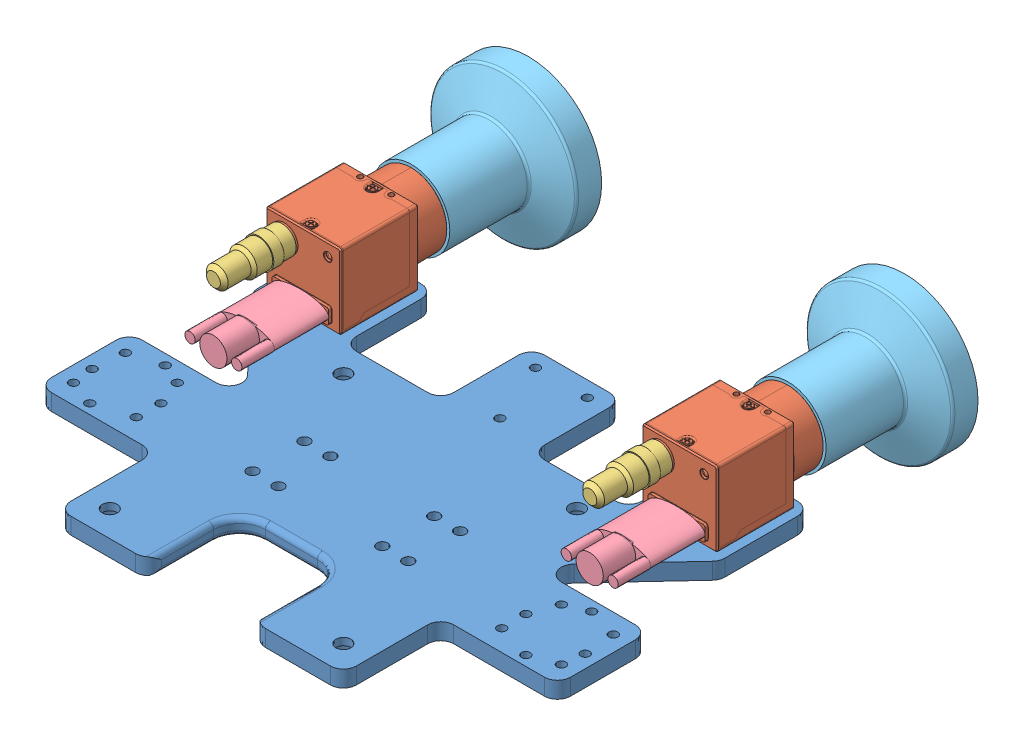
SolidWorks assembly cameras_on_plate, configuration Default. Lengths in mm.
Overall size (218.83 73.83 205.96).
11 component instances, 5 part files, 9 mates.
Components (placement in the parent):
- camera_plate-1: camera_plate [Default] at origin size (200 6.35 145)
- BFS_U3_fisheye-1: BFS_U3_fisheye [Default] at (72.5 20.85 -74.1182) x (-1 0 0) z (0 0 -1) size (73.83 73.83 128.56)
  - FL2-020-R0-1: FL2-020-R0 [Default] at origin size (29 29 47.76)
  - round_connector-1: round_connector [Default] at (7.25 7.25 -17.9182) x (0 0 -1) z (-0.517634 -0.855602 0) size (26.5 11.5 11.5)
  - wide_connector-1: wide_connector [Default] at (0 -9.325 -18.2182) x (1 0 0) z (0 0 -1) size (22 10.5 33.5)
  - FE185C086HA_1-2: FE185C086HA_1 [Default] at (0 0 16.3398) x (-0.923728 -0.383049 0) z (0 0 -1) size (56.5 56.5 60.5)
- BFS_U3_fisheye-3: BFS_U3_fisheye [Default] at (-72.5 20.85 -74.1182) x (-1 0 0) z (0 0 -1) size (73.83 73.83 128.56)
  - FL2-020-R0-1: FL2-020-R0 [Default] at origin size (29 29 47.76)
  - round_connector-1: round_connector [Default] at (7.25 7.25 -17.9182) x (0 0 -1) z (-0.517634 -0.855602 0) size (26.5 11.5 11.5)
  - wide_connector-1: wide_connector [Default] at (0 -9.325 -18.2182) x (1 0 0) z (0 0 -1) size (22 10.5 33.5)
  - FE185C086HA_1-2: FE185C086HA_1 [Default] at (0 0 16.3398) x (-0.923728 -0.383049 0) z (0 0 -1) size (56.5 56.5 60.5)
Mates (geometry in assembly coordinates):
- ProfileCenter1: profile center aligned: circle of camera_plate-1
- Concentric1: concentric aligned: cylinder of camera_plate-1 through (-82.5 0 -84) axis (0 -1 0) radius 3.25; cylinder of BFS-U3-31S4-1 through (-82.5 6.35 -84) axis (0 -1 0) radius 1.25
- ProfileCenter2: profile center: unknown of ?; unknown of camera_plate-1
- Concentric2: concentric aligned: cylinder of camera_plate-1 through (-10 0 -84) axis (0 -1 0) radius 3.25; cylinder of BFS-U3-31S4-3 through (-10 6.35 -84) axis (0 -1 0) radius 1.25
- ProfileCenter3: profile center: unknown of ?; unknown of camera_plate-1
- Concentric3: concentric aligned: cylinder of camera_plate-1 through (62.5 0 -84) axis (0 -1 0) radius 3.25; cylinder of BFS-U3-31S4-4 through (62.5 6.35 -84) axis (0 -1 0) radius 1.25
- Concentric4: concentric aligned: cylinder of camera_plate-1 through (72.5 0 -60.3) axis (0 -1 0) radius 1.7; cylinder of BFS_U3_fisheye-1/FL2-020-R0-1 through (72.5 6.35 -60.3) axis (0 -1 0) radius 1.5
- Concentric5: concentric aligned: cylinder of camera_plate-1 through (62.5 0 -84) axis (0 -1 0) radius 1.7; cylinder of BFS_U3_fisheye-1/FL2-020-R0-1 through (62.5 6.35 -84) axis (0 -1 0) radius 1.5
- Coincident1: coincident anti-aligned: plane of camera_plate-1 through (0 6.35 0) normal (0 1 0); plane of BFS_U3_fisheye-1/FL2-020-R0-1 through (86 6.35 -83.5) normal (0 -1 0)
